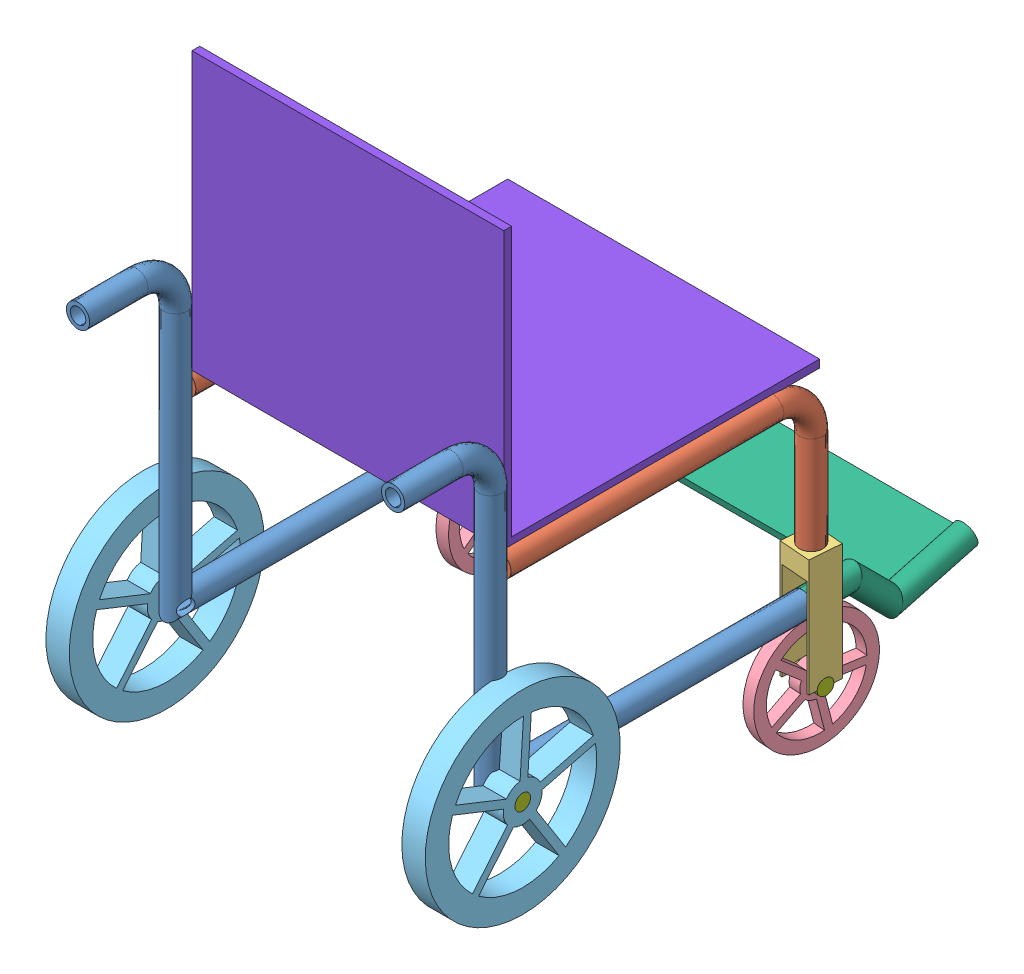
SolidWorks assembly Standard_wheelchair_model, configuration Default. Lengths in mm.
Overall size (973.01 1569.21 1579.02).
18 component instances, 8 part files, 23 mates.
Components (placement in the parent):
- side-2: side [Default] at (403.0752 499.0253 1111.4591) size (60 820 1050)
- handle-2: handle [Default] at (403.0752 882.2765 880.9703) size (60 380 830)
- rev-1: rev [Default] at (363.1965 382.2765 84.0821) x (0.996969 0 -0.077794) z (0.077794 0 0.996969) size (80 300 80)
- wheel_fr-3: wheel_fr [Default] at (388.1207 232.2765 82.1372) x (0.996969 0 -0.077794) z (-0.075516 0.24022 -0.967777) size (30 300 300)
- back wheel-1: back wheel [Default] at (320.7146 407.2765 903.331) x (1 0 0) z (0 -0.637823 -0.770183) size (60 500 500)
- foot_rest-2: foot_rest [Default] at (403.0752 407.2765 103.331) size (868.28 169.53 427.02)
- pin-1: pin [Default] at (363.1965 232.2765 84.0821) x (0.996969 0 -0.077794) z (0.077794 0 0.996969) size (40 40 40)
- pin-3: pin [Default] at (403.0752 232.2765 80.9703) x (0.996969 0 -0.077794) z (0.077794 0 0.996969) size (40 40 40)
- pin-5: pin [Default] at (320.7146 407.2765 903.331) x (1 0 0) z (0 0.25053 -0.968109) size (40 40 40)
- wheel_fr-4: wheel_fr [Default] at (1226.314 232.2765 82.1372) x (-0.996969 0 -0.077794) z (-0.075516 -0.24022 0.967777) size (30 300 300)
- pin-6: pin [Default] at (1251.2383 232.2765 84.0821) x (-0.996969 0 -0.077794) z (0.077794 0 -0.996969) size (40 40 40)
- rev-2: rev [Default] at (1251.2383 382.2765 84.0821) x (-0.996969 0 -0.077794) z (0.077794 0 -0.996969) size (80 300 80)
- handle-3: handle [Default] at (1211.3595 882.2765 880.9703) size (60 380 830)
- back wheel-2: back wheel [Default] at (1293.7202 407.2765 903.331) x (-1 0 0) z (0 0.637823 0.770183) size (60 500 500)
- pin-7: pin [Default] at (1293.7202 407.2765 903.331) x (-1 0 0) z (0 -0.25053 0.968109) size (40 40 40)
- side-3: side [Default] at (1211.3595 499.0253 1111.4591) size (60 820 1050)
- pin-8: pin [Default] at (1211.3595 232.2765 80.9703) x (-0.996969 0 -0.077794) z (0.077794 0 -0.996969) size (40 40 40)
- seat-1: seat [Default] at (413.0694 919.8459 861.1204) size (800 710 810)
Mates (geometry in assembly coordinates):
- Coincident4: coincident aligned: line of side-2 through (403.0752 882.2765 892.4591) axis (0 0 -1); line of handle-2 through (403.0752 882.2765 880.9703) axis (0 0 -1)
- Coincident5: coincident anti-aligned: cylinder of side-2 through (403.0752 882.2765 892.4591) axis (0 0 -1) radius 20; circle of handle-2
- Tangent3: tangent: curve of side-2; circle of handle-2
- Parallel3: parallel aligned: plane of handle-2 through (403.0752 882.2765 880.9703) normal (1 0 0)
- Coincident7: coincident aligned: circle of handle-2; circle of rev-1
- Coincident9: coincident aligned: line of rev-1 through (368.1813 232.2765 83.6931) axis (-0.996969 0 0.077794); line of wheel_fr-2 through (416.2105 232.2765 80.9703) axis (-1 0 0)
- Coincident13: coincident aligned: line of rev-1 through (368.1813 232.2765 83.6931) axis (-0.996969 0 0.077794); line of wheel_fr-3 through (418.0298 232.2765 79.8034) axis (-0.996969 0 0.077794)
- Distance3: distance = 20 mm anti-aligned: plane of wheel_fr-3 through (388.1207 232.2765 82.1372) normal (-0.996969 0 0.077794); plane of rev-1 through (365.0695 482.2765 43.8143) normal (0.996969 0 -0.077794)
- Parallel6: parallel anti-aligned: line of side-2 through (403.0752 407.2765 903.331) axis (1 0 0); line of back wheel-1 through (380.7146 407.2765 903.331) axis (-1 0 0)
- Coincident17: coincident anti-aligned: line of side-2 through (376.6177 407.2765 903.331) axis (1 0 0); line of back wheel-1 through (380.7146 407.2765 903.331) axis (-1 0 0)
- Tangent8: tangent: curve of side-2; circle of back wheel-1
- Coincident18: coincident aligned: circle of side-2; circle of foot_rest-2
- Parallel7: parallel aligned: plane of foot_rest-2 through (403.0752 407.2765 103.331) normal (1 0 0)
- Concentric2: concentric aligned: cylinder of wheel_fr-3 through (418.0298 232.2765 79.8034) axis (-0.996969 0 0.077794) radius 20; cylinder of pin-1 through (403.0752 232.2765 80.9703) axis (-0.996969 0 0.077794) radius 20
- Coincident20: coincident aligned: plane of rev-1 through (363.1965 232.2765 84.0821) normal (-0.996969 0 0.077794); plane of pin-1 through (363.1965 232.2765 84.0821) normal (-0.996969 0 0.077794)
- Concentric3: concentric aligned: cylinder of wheel_fr-3 through (418.0298 232.2765 79.8034) axis (-0.996969 0 0.077794) radius 20; cylinder of pin-3 through (442.954 232.2765 77.8585) axis (-0.996969 0 0.077794) radius 20
- Coincident21: coincident aligned: plane of rev-1 through (442.954 232.2765 77.8585) normal (0.996969 0 -0.077794); plane of pin-3 through (442.954 232.2765 77.8585) normal (0.996969 0 -0.077794)
- Concentric4: concentric aligned: cylinder of back wheel-1 through (380.7146 407.2765 903.331) axis (-1 0 0) radius 20; line of pin-5 through (360.7146 407.2765 903.331) axis (-1 0 0)
- Concentric5: concentric aligned: cylinder of back wheel-1 through (380.7146 407.2765 903.331) axis (-1 0 0) radius 20; cylinder of pin-5 through (360.7146 407.2765 903.331) axis (-1 0 0) radius 20
- Concentric7: concentric aligned: cylinder of back wheel-1 through (380.7146 407.2765 903.331) axis (-1 0 0) radius 20; cylinder of pin-5 through (360.7146 407.2765 903.331) axis (-1 0 0) radius 20
- Concentric8: concentric aligned: cylinder of back wheel-1 through (380.7146 407.2765 903.331) axis (-1 0 0) radius 20; cylinder of pin-5 through (360.7146 407.2765 903.331) axis (-1 0 0) radius 20
- Coincident22: coincident aligned: plane of back wheel-1 through (320.7146 407.2765 903.331) normal (-1 0 0); plane of pin-5 through (320.7146 407.2765 903.331) normal (-1 0 0)
- GearMate1: gear = 100 : 80 mm: circle of wheel_fr-3; circle of back wheel-1
